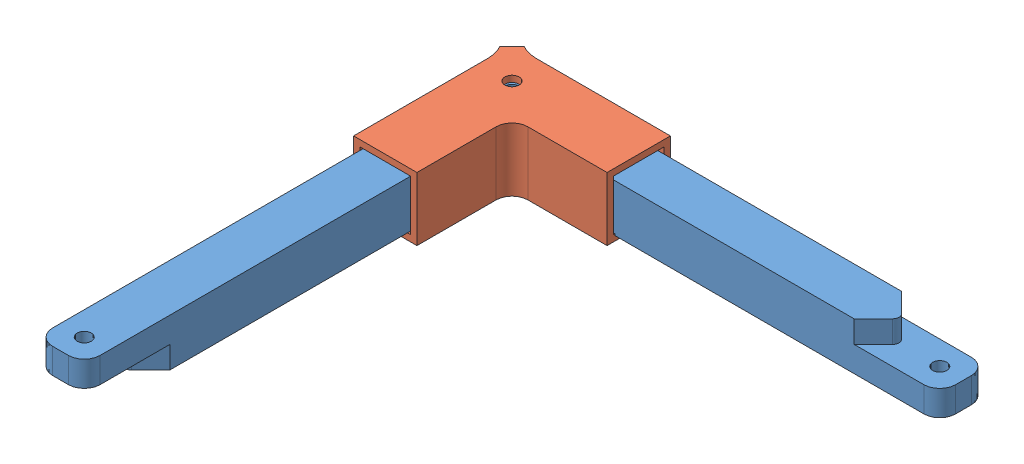
SolidWorks assembly BeamDemoAssembly, configuration Default. Lengths in mm.
Overall size (153.91 20 153.91).
3 component instances, 2 part files, 6 mates.
Components (placement in the parent):
- Beam-1: Beam [Default] at (-105.5884 -6.3887 22.8861) size (150 15 15)
- Beam-2: Beam [Default] at (-105.5884 9.6113 157.8861) x (0 0 -1) z (-1 0 0) size (150 15 15)
- 90degbracket-1: 90degbracket [Default] at (-58.0884 -7.8887 5.3861) x (0 0 1) z (-1 0 0) size (51.41 20 51.41)
Mates (geometry in assembly coordinates):
- Coincident1: coincident anti-aligned: plane of Beam-1 through (44.4116 1.6113 22.8861) normal (0 1 0); plane of Beam-2 through (-105.5884 1.6113 157.8861) normal (0 -1 0)
- Concentric1: concentric anti-aligned: cylinder of Beam-1 through (-98.0884 -12.7527 15.3861) axis (0 1 0) radius 2.25; cylinder of Beam-2 through (-98.0884 15.9752 15.3861) axis (0 -1 0) radius 2.25
- Coincident2: coincident aligned: plane of Beam-1 through (-105.5884 8.6113 22.8861) normal (-1 0 0); plane of Beam-2 through (-105.5884 -5.3887 157.8861) normal (-1 0 0)
- Width1: width anti-aligned: plane of Beam-2 through (-90.5884 -5.3887 157.8861) normal (1 0 0); plane of 90degbracket-1 through (-105.5884 -5.3887 157.8861) normal (-1 0 0); plane of Beam-2 through (-90.0884 10.1113 55.3861) normal (-1 0 0); plane of 90degbracket-1 through (-106.0884 10.1113 55.3861) normal (1 0 0)
- Width2: width aligned: plane of 90degbracket-1 through (-88.0884 -5.8887 7.3861) normal (0 1 0); plane of Beam-2 through (-88.0884 10.1113 7.3861) normal (0 -1 0); plane of 90degbracket-1 through (-105.5884 9.6113 157.8861) normal (0 1 0); plane of Beam-2 through (-105.5884 -5.3887 157.8861) normal (0 -1 0)
- Width3: width anti-aligned: plane of 90degbracket-1 through (-88.0884 -5.8887 7.3861) normal (0 0 1); plane of Beam-1 through (-88.0884 -5.8887 23.3861) normal (0 0 -1); plane of 90degbracket-1 through (-105.5884 8.6113 7.8861) normal (0 0 -1); plane of Beam-1 through (-105.5884 8.6113 22.8861) normal (0 0 1)
